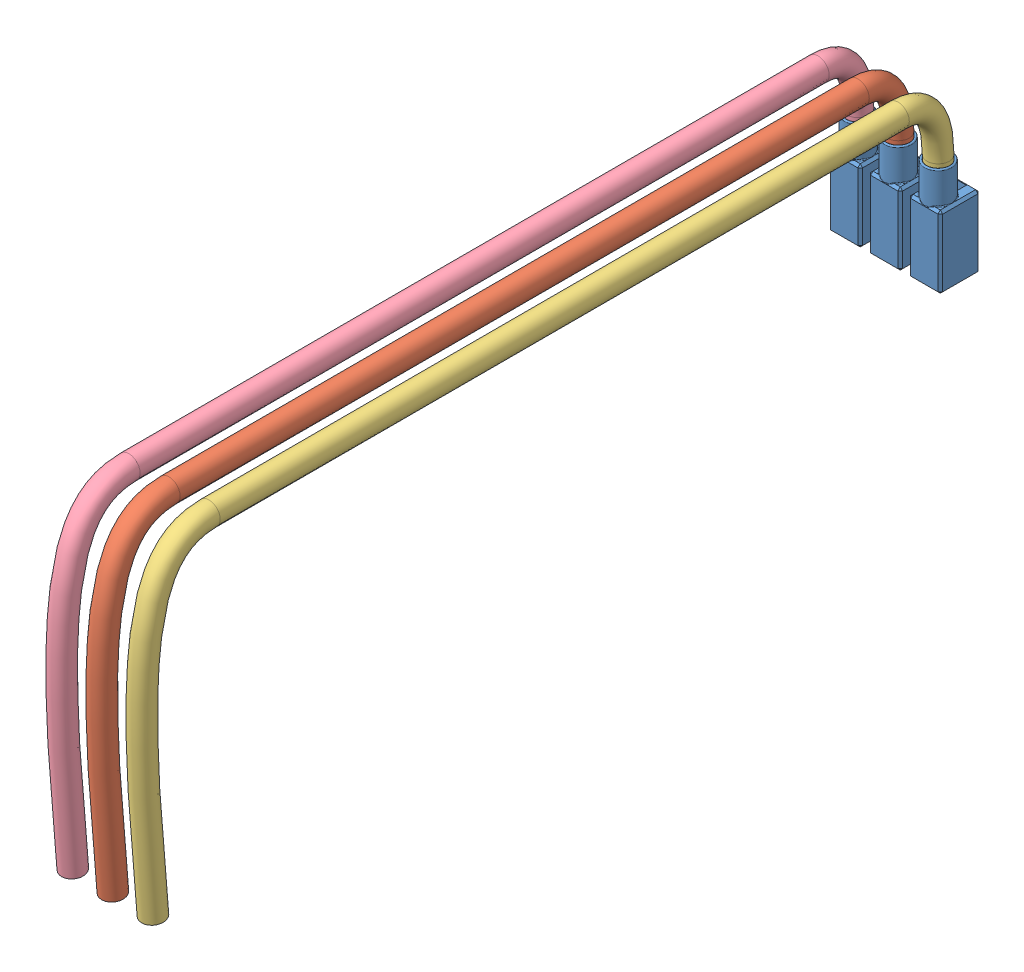
SolidWorks assembly Xstop wire assembly, configuration Default. Lengths in mm.
Overall size (9.8 20.77 53.74).
7 component instances, 4 part files, 12 mates.
Components (placement in the parent):
- JST Endstop connector assembly-1: JST Endstop connector assembly [Default] at origin size (7 6.61 2.5)
  - JSH XHP Contact Pin-1: JSH XHP Contact Pin [Default] at (-2.5 1 0.25) size (2 6.61 2.5)
  - JSH XHP Contact Pin-2: JSH XHP Contact Pin [Default] at (0 1 0.25) size (2 6.61 2.5)
  - JSH XHP Contact Pin-3: JSH XHP Contact Pin [Default] at (2.5 1 0.25) size (2 6.61 2.5)
- XStop wire Black-1: XStop wire Black [Default] at (0 5.7 0.6354) size (1.4 20.77 51.11)
- XStop wire Red-1: XStop wire Red [Default] at (2.5 5.7 0.6354) size (1.4 20.77 51.11)
- XStop wire white-1: XStop wire white [Default] at (-2.5 5.7 0.6354) size (1.4 20.77 51.11)
Mates (geometry in assembly coordinates):
- Coincident1: coincident: plane of JST Endstop connector assembly-1 through (0 0 0) normal (0 0 1); plane of assembly through (0 0 0) normal (0 0 1)
- Coincident2: coincident: plane of JST Endstop connector assembly-1 through (0 0 0) normal (0 1 0); plane of assembly through (0 0 0) normal (0 1 0)
- Coincident3: coincident: plane of JST Endstop connector assembly-1 through (0 0 0) normal (1 0 0); plane of assembly through (0 0 0) normal (1 0 0)
- Concentric1: concentric: cylinder of JST Endstop connector assembly-1/JSH XHP Contact Pin-3 through (2.5 7.5 0.6354) axis (0 -1 0) radius 0.7; cylinder of XStop wire Red-1 through (2.5 7.7 0.6354) axis (0 -1 0) radius 0.7
- Concentric2: concentric: cylinder of JST Endstop connector assembly-1/JSH XHP Contact Pin-2 through (0 7.5 0.6354) axis (0 -1 0) radius 0.7; cylinder of XStop wire Black-1 through (0 7.7 0.6354) axis (0 -1 0) radius 0.7
- Concentric3: concentric: cylinder of JST Endstop connector assembly-1/JSH XHP Contact Pin-1 through (-2.5 7.5 0.6354) axis (0 -1 0) radius 0.7; cylinder of XStop wire white-1 through (-2.5 7.7 0.6354) axis (0 -1 0) radius 0.7
- Coincident4: coincident: plane of XStop wire Black-1 through (0 5.7 0.6354) normal (0 -1 0); plane of XStop wire Red-1 through (2.5 5.7 0.6354) normal (0 -1 0)
- Coincident5: coincident: plane of XStop wire Red-1 through (2.5 5.7 0.6354) normal (0 -1 0); plane of XStop wire white-1 through (-2.5 5.7 0.6354) normal (0 -1 0)
- Parallel1: parallel: plane of JST Endstop connector assembly-1 through (0 0 0) normal (1 0 0); plane of XStop wire Black-1 through (0 5.7 0.6354) normal (1 0 0)
- Parallel2: parallel: plane of JST Endstop connector assembly-1 through (0 0 0) normal (1 0 0); plane of XStop wire Red-1 through (2.5 5.7 0.6354) normal (1 0 0)
- Parallel3: parallel: plane of JST Endstop connector assembly-1 through (0 0 0) normal (1 0 0); plane of XStop wire white-1 through (-2.5 5.7 0.6354) normal (1 0 0)
- Coincident9: coincident: plane of JST Endstop connector assembly-1/JSH XHP Contact Pin-3 through (2.5 5.7 0.6354) normal (0 1 0); plane of XStop wire Red-1 through (2.5 5.7 0.6354) normal (0 -1 0)
